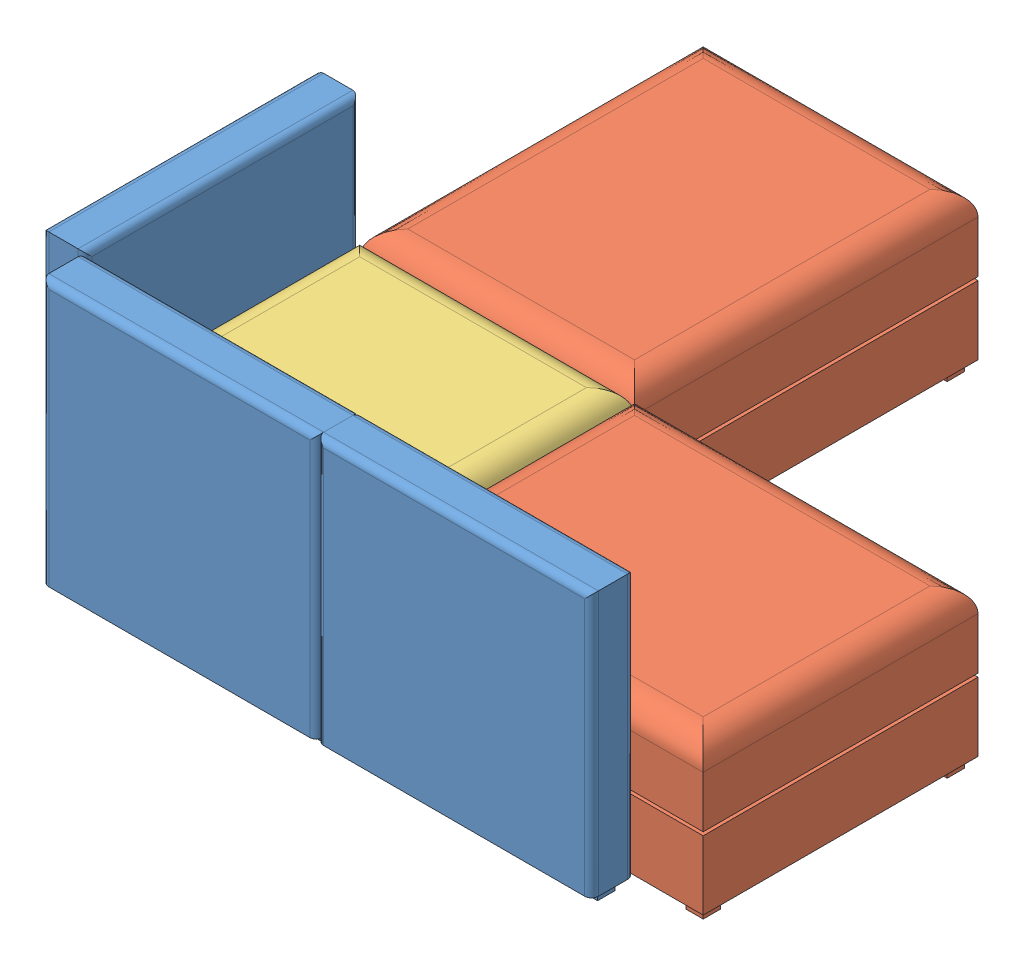
SolidWorks assembly Baugruppe3, configuration Standard. Lengths in mm.
Overall size (1925 800 1925).
6 component instances, 3 part files, 18 mates.
Components (placement in the parent):
- Rückenstütze-80x80-1: Rückenstütze-80x80 [Standard] at (-600 -800 -62.5) x (1 0 0) z (0 1 0) size (800 125 800)
- Sitzelement-1: Sitzelement [Standard] at (-1400 -770 -1425) size (800 460 1000)
- Sitzelement-mit-Aufb-1: Sitzelement-mit-Aufb [Standard] at (-1400 -770 -525) size (800 460 800)
- Sitzelement-2: Sitzelement [Standard] at (-500 -770 -525) x (0 0 1) z (-1 0 0) size (800 460 1000)
- Rückenstütze-80x80-2: Rückenstütze-80x80 [Standard] at (-1400 -800 -62.5) x (1 0 0) z (0 1 0) size (800 125 800)
- Rückenstütze-80x80-3: Rückenstütze-80x80 [Standard] at (-1862.5 -800 -525) x (0 0 1) z (0 1 0) size (800 125 800)
Mates (geometry in assembly coordinates):
- Deckungsgleich1: coincident anti-aligned: plane of Sitzelement-mit-Aufb-1 through (-1000 -570 180.2562) normal (1 0 0); plane of Sitzelement-2 through (-1000 -570 -619.7438) normal (-1 0 0)
- Deckungsgleich2: coincident aligned: plane of Sitzelement-mit-Aufb-1 through (-1800 -570 180.2562) normal (0 0 1); plane of Sitzelement-2 through (-1000 -570 180.2562) normal (0 0 1)
- Deckungsgleich3: coincident anti-aligned: plane of Sitzelement-1 through (-1800 -570 -619.7438) normal (0 0 1); plane of Sitzelement-mit-Aufb-1 through (-1800 -570 -619.7438) normal (0 0 -1)
- Deckungsgleich4: coincident aligned: plane of Sitzelement-1 through (-1800 -570 -619.7438) normal (-1 0 0); plane of Sitzelement-mit-Aufb-1 through (-1800 -570 180.2562) normal (-1 0 0)
- Deckungsgleich5: coincident anti-aligned: plane of Rückenstütze-80x80-1 through (-1000 0 180.2562) normal (0 0 -1); plane of Sitzelement-2 through (-1000 -570 180.2562) normal (0 0 1)
- Deckungsgleich6: coincident anti-aligned: plane of Sitzelement-mit-Aufb-1 through (-1800 -570 180.2562) normal (0 0 1); plane of Rückenstütze-80x80-2 through (-1800 0 180.2562) normal (0 0 -1)
- Deckungsgleich7: coincident anti-aligned: plane of Sitzelement-mit-Aufb-1 through (-1800 -570 180.2562) normal (-1 0 0); plane of Rückenstütze-80x80-3 through (-1800 0 -619.7438) normal (1 0 0)
- Deckungsgleich8: coincident anti-aligned: plane of Rückenstütze-80x80-1 through (-1000 0 305.2562) normal (-1 0 0); plane of Sitzelement-mit-Aufb-1 through (-1000 -570 180.2562) normal (1 0 0)
- Deckungsgleich9: coincident aligned: plane of Sitzelement-mit-Aufb-1 through (-1800 -570 180.2562) normal (-1 0 0); plane of Rückenstütze-80x80-2 through (-1800 0 305.2562) normal (-1 0 0)
- Deckungsgleich10: coincident aligned: plane of Sitzelement-mit-Aufb-1 through (-1800 -570 180.2562) normal (0 0 1); plane of Rückenstütze-80x80-3 through (-1925 0 180.2562) normal (0 0 1)
- Deckungsgleich11: coincident aligned: plane of Rückenstütze-80x80-1 through (-600 -800 242.7562) normal (0 -1 0); plane of Sitzelement-2 through (-500 -800 -219.7438) normal (0 -1 0)
- Deckungsgleich12: coincident aligned: plane of Sitzelement-mit-Aufb-1 through (-1400 -800 -219.7438) normal (0 -1 0); plane of Sitzelement-2 through (-500 -800 -219.7438) normal (0 -1 0)
- Deckungsgleich13: coincident aligned: plane of Sitzelement-mit-Aufb-1 through (-1400 -800 -219.7438) normal (0 -1 0); plane of Rückenstütze-80x80-2 through (-1400 -800 242.7562) normal (0 -1 0)
- Deckungsgleich14: coincident aligned: plane of Sitzelement-mit-Aufb-1 through (-1400 -800 -219.7438) normal (0 -1 0); plane of Rückenstütze-80x80-3 through (-1862.5 -800 -219.7438) normal (0 -1 0)
- Deckungsgleich15: coincident aligned: plane of Sitzelement-1 through (-1400 -800 -1119.7438) normal (0 -1 0); plane of Sitzelement-mit-Aufb-1 through (-1400 -800 -219.7438) normal (0 -1 0)
- Deckungsgleich16: coincident aligned: plane of Rückenstütze-80x80-2 through (-1400 0 -62.5) normal (0 1 0); plane of assembly
- Deckungsgleich17: coincident aligned: plane of Sitzelement-2 through (0 -570 -925) normal (1 0 0); plane of assembly
- Deckungsgleich18: coincident aligned: plane of Rückenstütze-80x80-2 through (-1800 0 0) normal (0 0 1); plane of assembly
